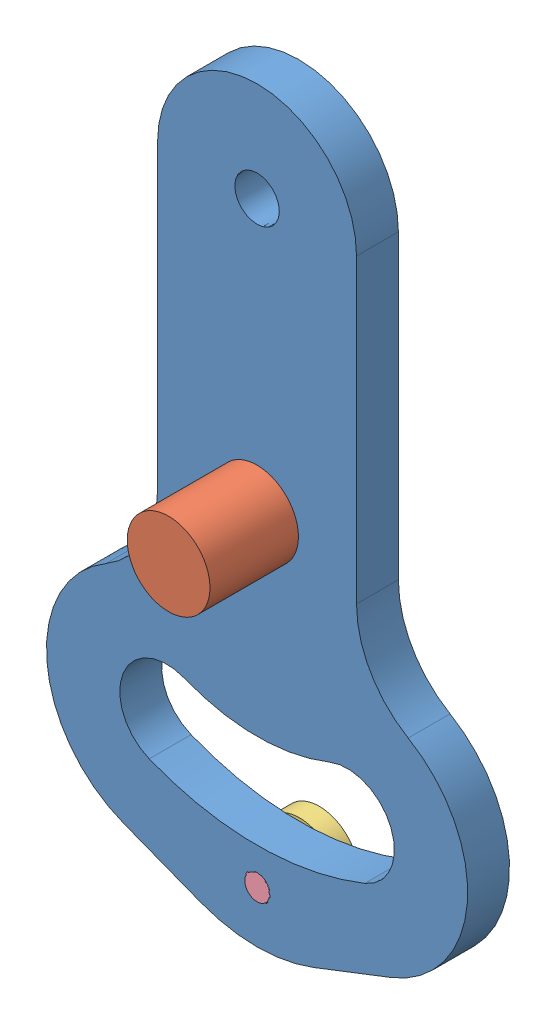
SolidWorks assembly ТП.002.04.00 - Рычаг перекидной, configuration 00. Lengths in mm.
Overall size (80.46 142.82 29.3).
4 component instances, 4 part files, 14 mates.
Components (placement in the parent):
- ТП.002.04.01 - Рычаг толкатель-1: ТП.002.04.01 - Рычаг толкатель [По умолчанию] at origin size (80.46 142.82 8)
- ТП.002.04.02 - Ось прекидушки-1: ТП.002.04.02 - Ось прекидушки [00] at (0.1381 0.0002 24.9) x (0.999998 0.002227 0) z (0 0 1) size (15.8 15.8 24.9)
- ТП.002.04.04 - Ролик толкающий-1: ТП.002.04.04 - Ролик толкающий [--] at (0 0 -3.9) x (-1 0 0) z (0 0 -1) size (15 15 3.8)
- ТП.002.04.03 - Ось ролика-1: ТП.002.04.03 - Ось ролика [--] at (0 0 -3.9) x (-1 0 0) z (0 0 -1) size (5 5 12.4)
Mates (geometry in assembly coordinates):
- Концентричный1: concentric: cylinder of ТП.002.04.01 - Рычаг толкатель-1 through (0 62 8) axis (0 0 -1) radius 7.9; cylinder of ТП.002.04.02 - Ось прекидушки-1 through (0 62 -22.3446) axis (0 0 1) radius 7.9
- Совпадение1: coincident: plane of ТП.002.04.01 - Рычаг толкатель-1 through (-17.2319 19.3495 0) normal (0 0 -1); plane of ТП.002.04.02 - Ось прекидушки-1 through (-2.9937 69.3108 0) normal (0 0 -1)
- На месте1: in place: plane of ТП.002.04.01 - Рычаг толкатель-1 through (-17.2319 19.3495 0) normal (0 0 -1); plane of ? through (0 0 0) normal (0 0 -1); moOrthogonalPlaneRef_w of ТП.002.04.01 - Рычаг толкатель-1 through (-17.2319 19.3495 0) normal (0 0 -1); plane of ? through (0 0 0) normal (0 1 0); plane of ТП.002.04.01 - Рычаг толкатель-1 through (-17.2319 19.3495 0) normal (0 0 -1); plane of ? through (0 0 0) normal (-1 0 0); plane of ТП.002.04.01 - Рычаг толкатель-1 through (-17.2319 19.3495 0) normal (0 0 -1); unknown of ?
- Совпадение2: coincident: plane of ТП.002.04.01 - Рычаг толкатель-1; plane of ?
- Совпадение3: coincident: moOrthogonalPlaneRef_w of ТП.002.04.01 - Рычаг толкатель-1 through (0 0 0) normal (0 1 0); plane of ? through (0 0 0) normal (0 1 0)
- Совпадение4: coincident: moOrthogonalPlaneRef_w of ТП.002.04.01 - Рычаг толкатель-1 through (0 0 0) normal (1 0 0); plane of ? through (0 0 0) normal (-1 0 0)
- На месте2: in place: plane of ? through (0 0 -3.9) normal (0 0 -1); plane of ? through (0 0 -3.9) normal (0 0 -1); plane of ? through (0 0 -3.9) normal (0 0 -1); plane of ? through (0 0 -3.9) normal (0 1 0); plane of ? through (0 0 -3.9) normal (0 0 -1); plane of ? through (0 0 -3.9) normal (-1 0 0); plane of ? through (0 0 -3.9) normal (0 0 -1); unknown of ?
- Совпадение5: coincident: plane of ?; plane of ТП.002.04.04 - Ролик толкающий-1
- Совпадение6: coincident: moOrthogonalPlaneRef_w of ? through (0 0 -3.9) normal (0 1 0); plane of ТП.002.04.04 - Ролик толкающий-1 through (0 0 -3.9) normal (0 1 0)
- Совпадение7: coincident: moOrthogonalPlaneRef_w of ? through (0 0 -3.9) normal (1 0 0); plane of ТП.002.04.04 - Ролик толкающий-1 through (0 0 -3.9) normal (-1 0 0)
- На месте3: in place: plane of ? through (0 0 -3.9) normal (0 0 -1); plane of ? through (0 0 -3.9) normal (0 0 -1); plane of ? through (0 0 -3.9) normal (0 0 -1); plane of ? through (0 0 -3.9) normal (0 1 0); plane of ? through (0 0 -3.9) normal (0 0 -1); plane of ? through (0 0 -3.9) normal (-1 0 0); plane of ? through (0 0 -3.9) normal (0 0 -1); unknown of ?
- Совпадение2: coincident: plane of ТП.002.04.04 - Ролик толкающий-1; plane of ТП.002.04.03 - Ось ролика-1
- Совпадение3: coincident: moOrthogonalPlaneRef_w of ТП.002.04.04 - Ролик толкающий-1 through (0 0 -3.9) normal (0 1 0); plane of ТП.002.04.03 - Ось ролика-1 through (0 0 -3.9) normal (0 1 0)
- Совпадение4: coincident: moOrthogonalPlaneRef_w of ТП.002.04.04 - Ролик толкающий-1 through (0 0 -3.9) normal (1 0 0); plane of ТП.002.04.03 - Ось ролика-1 through (0 0 -3.9) normal (-1 0 0)
